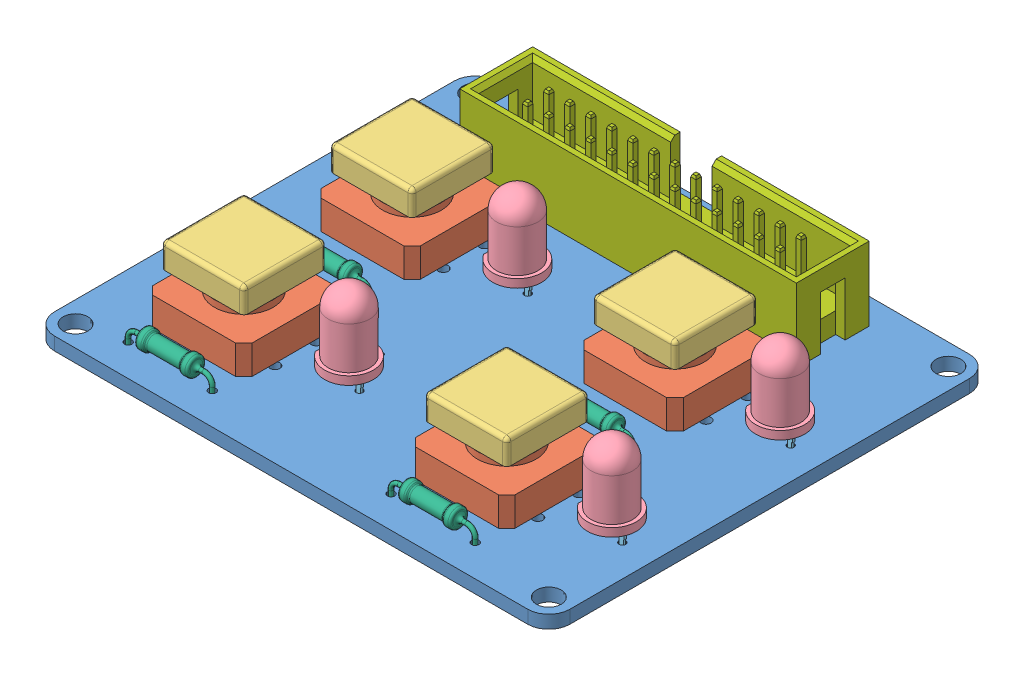
SolidWorks assembly Assembled PCB, configuration Default. Lengths in mm.
Overall size (62.23 14.18 53.34).
30 component instances, 7 part files, 39 mates.
Components (placement in the parent):
- PCB-1: PCB [Default] at (23.5423 23.7207 53.0141) size (62.23 1.57 53.34)
- Button Assembly-1: Button Assembly [Default] at (104.7843 22.09 18.5104) size (12 10.4 12)
  - button-1: button [Default] at (-99.657 3.2054 48.4737) size (12 8.9 12)
  - Cap-2: Cap [Default] at (-99.657 12.0054 48.4737) size (10 4.5 10)
- Button Assembly-2: Button Assembly [Default] at (104.7843 22.09 -1.8054) size (12 10.4 12)
  - button-1: button [Default] at (-99.657 3.2054 48.4737) size (12 8.9 12)
  - Cap-2: Cap [Default] at (-99.657 12.0054 48.4737) size (10 4.5 10)
- Button Assembly-3: Button Assembly [Default] at (136.5343 22.09 18.5104) size (12 10.4 12)
  - button-1: button [Default] at (-99.657 3.2054 48.4737) size (12 8.9 12)
  - Cap-2: Cap [Default] at (-99.657 12.0054 48.4737) size (10 4.5 10)
- Button Assembly-4: Button Assembly [Default] at (136.5343 22.09 -1.8054) size (12 10.4 12)
  - button-1: button [Default] at (-99.657 3.2054 48.4737) size (12 8.9 12)
  - Cap-2: Cap [Default] at (-99.657 12.0054 48.4737) size (10 4.5 10)
- LED short-1: LED short [Default] at (17.8273 29.3722 66.9841) x (-1 0 0) z (0 0 -1) size (5.45 13.1 5.9)
  - LED Head-1: LED Head [Default] at origin size (5.45 8.6 5.9)
  - LED Leads-1: LED Leads [Default] at (0 -5.1452 0) size (4.04 8 0.3)
- LED short-3: LED short [Default] at (17.8273 29.3722 46.6641) x (-1 0 0) z (0 0 -1) size (5.45 13.1 5.9)
  - LED Head-1: LED Head [Default] at origin size (5.45 8.6 5.9)
  - LED Leads-1: LED Leads [Default] at (0 -5.1452 0) size (4.04 8 0.3)
- LED short-4: LED short [Default] at (49.5773 29.3722 46.6641) x (-1 0 0) z (0 0 -1) size (5.45 13.1 5.9)
  - LED Head-1: LED Head [Default] at origin size (5.45 8.6 5.9)
  - LED Leads-1: LED Leads [Default] at (0 -5.1452 0) size (4.04 8 0.3)
- LED short-5: LED short [Default] at (49.5773 29.3722 66.9841) x (-1 0 0) z (0 0 -1) size (5.45 13.1 5.9)
  - LED Head-1: LED Head [Default] at origin size (5.45 8.6 5.9)
  - LED Leads-1: LED Leads [Default] at (0 -5.1452 0) size (4.04 8 0.3)
- Resistor .4-1: Resistor .4 [Default] at (5.1273 26.7955 56.8241) size (10.67 6.22 2.29)
- Resistor .4-2: Resistor .4 [Default] at (5.1273 26.7955 75.8741) size (10.67 6.22 2.29)
- Resistor .4-3: Resistor .4 [Default] at (36.8773 26.7955 56.8241) x (-1 0 0) z (0 0 -1) size (10.67 6.22 2.29)
- Resistor .4-4: Resistor .4 [Default] at (36.8773 26.7955 75.8741) x (-1 0 0) z (0 0 -1) size (10.67 6.22 2.29)
- header-1: header [Default] at (22.9073 25.3955 33.9641) x (-1 0 0) z (0 0 -1) size (40.64 11.9 8.8)
Mates (geometry in assembly coordinates):
- Concentric1: concentric aligned: cylinder of PCB-1 through (5.1273 23.7207 71.4841) axis (0 1 0) radius 0.9017; cylinder of Button Assembly-1/button-1 through (5.1273 23.6955 71.4841) axis (0 1 0) radius 0.9
- Parallel1: parallel aligned: cylinder of PCB-1 through (5.1273 23.7207 62.4883) axis (0 1 0) radius 0.9017; cylinder of Button Assembly-1/button-1 through (5.1273 23.6955 62.4841) axis (0 1 0) radius 0.9
- Coincident1: coincident anti-aligned: plane of PCB-1 through (52.1173 25.2955 28.8841) normal (0 1 0); plane of Button Assembly-1/button-1 through (5.1273 25.2955 66.9841) normal (0 -1 0)
- Concentric3: concentric aligned: cylinder of PCB-1 through (5.1273 23.7207 42.1683) axis (0 1 0) radius 0.9017; cylinder of Button Assembly-2/button-1 through (5.1273 23.6955 42.1683) axis (0 1 0) radius 0.9
- Parallel2: parallel aligned: cylinder of PCB-1 through (5.1273 23.7207 51.1641) axis (0 1 0) radius 0.9017; cylinder of Button Assembly-2/button-1 through (5.1273 23.6955 51.1683) axis (0 1 0) radius 0.9
- Coincident2: coincident anti-aligned: plane of PCB-1 through (52.1173 25.2955 28.8841) normal (0 1 0); plane of Button Assembly-2/button-1 through (5.1273 25.2955 46.6683) normal (0 -1 0)
- Concentric5: concentric aligned: cylinder of PCB-1 through (36.8773 23.7207 71.4841) axis (0 1 0) radius 0.9017; cylinder of Button Assembly-3/button-1 through (36.8773 23.6955 71.4841) axis (0 1 0) radius 0.9
- Parallel3: parallel aligned: cylinder of PCB-1 through (36.8773 23.7207 62.4883) axis (0 1 0) radius 0.9017; cylinder of Button Assembly-3/button-1 through (36.8773 23.6955 62.4841) axis (0 1 0) radius 0.9
- Coincident3: coincident anti-aligned: plane of PCB-1 through (52.1173 25.2955 28.8841) normal (0 1 0); plane of Button Assembly-3/button-1 through (36.8773 25.2955 66.9841) normal (0 -1 0)
- Concentric7: concentric aligned: cylinder of PCB-1 through (36.8773 23.7207 42.1683) axis (0 1 0) radius 0.9017; cylinder of Button Assembly-4/button-1 through (36.8773 23.6955 42.1683) axis (0 1 0) radius 0.9
- Parallel4: parallel aligned: cylinder of PCB-1 through (36.8773 23.7207 51.1641) axis (0 1 0) radius 0.9017; cylinder of Button Assembly-4/button-1 through (36.8773 23.6955 51.1683) axis (0 1 0) radius 0.9
- Coincident4: coincident anti-aligned: plane of PCB-1 through (52.1173 25.2955 28.8841) normal (0 1 0); plane of Button Assembly-4/button-1 through (36.8773 25.2955 46.6683) normal (0 -1 0)
- Parallel5: parallel anti-aligned: line of PCB-1 through (-7.5727 25.2955 28.8841) axis (0 0 1); line of LED short-1/LED Head-1 through (15.3273 25.7955 68.5501) axis (0 0 -1)
- Distance2: distance = 2 mm anti-aligned: plane of LED short-1/LED Head-1 through (17.8273 27.2955 66.9841) normal (0 -1 0); plane of PCB-1 through (52.1173 25.2955 28.8841) normal (0 1 0)
- Concentric8: concentric: point of LED short-1/LED Leads-1; cylinder of PCB-1 through (16.5573 23.7207 66.9841) axis (0 1 0) radius 0.4064
- Parallel7: parallel anti-aligned: line of PCB-1 through (-7.5727 25.2955 28.8841) axis (0 0 1); line of LED short-3/LED Head-1 through (15.3273 25.7955 48.2301) axis (0 0 -1)
- Distance4: distance = 2 mm anti-aligned: plane of LED short-3/LED Head-1 through (17.8273 27.2955 46.6641) normal (0 -1 0); plane of PCB-1 through (52.1173 25.2955 28.8841) normal (0 1 0)
- Concentric9: concentric: cylinder of PCB-1 through (16.5573 23.7207 46.6641) axis (0 1 0) radius 0.4064; point of LED short-3/LED Leads-1
- Parallel8: parallel anti-aligned: line of PCB-1 through (-7.5727 25.2955 28.8841) axis (0 0 1); line of LED short-4/LED Head-1 through (47.0773 25.7955 48.2301) axis (0 0 -1)
- Distance5: distance = 2 mm anti-aligned: plane of LED short-4/LED Head-1 through (49.5773 27.2955 46.6641) normal (0 -1 0); plane of PCB-1 through (52.1173 25.2955 28.8841) normal (0 1 0)
- Concentric10: concentric: cylinder of PCB-1 through (48.3073 23.7207 46.6641) axis (0 1 0) radius 0.4064; point of LED short-4/LED Leads-1
- Parallel9: parallel anti-aligned: line of PCB-1 through (-7.5727 25.2955 28.8841) axis (0 0 1); line of LED short-5/LED Head-1 through (47.0773 25.7955 68.5501) axis (0 0 -1)
- Distance6: distance = 2 mm anti-aligned: plane of LED short-5/LED Head-1 through (49.5773 27.2955 66.9841) normal (0 -1 0); plane of PCB-1 through (52.1173 25.2955 28.8841) normal (0 1 0)
- Concentric11: concentric: cylinder of PCB-1 through (48.3073 23.7207 66.9841) axis (0 1 0) radius 0.4064; point of LED short-5/LED Leads-1
- Concentric12: concentric anti-aligned: cylinder of PCB-1 through (0.0473 23.7207 56.8241) axis (0 1 0) radius 0.45; cylinder of Resistor .4-1 through (0.0473 25.7955 56.8241) axis (0 -1 0) radius 0.254
- Concentric13: concentric anti-aligned: cylinder of PCB-1 through (10.2073 23.7207 56.8241) axis (0 1 0) radius 0.45; cylinder of Resistor .4-1 through (10.2073 25.7955 56.8241) axis (0 -1 0) radius 0.254
- Distance7: distance = 1.5 mm: line of Resistor .4-1 through (7.0669 26.7955 56.8241) axis (-1 0 0); plane of PCB-1 through (52.1173 25.2955 28.8841) normal (0 1 0)
- Distance8: distance = 1.5 mm: line of Resistor .4-2 through (7.0669 26.7955 75.8741) axis (-1 0 0); plane of PCB-1 through (52.1173 25.2955 28.8841) normal (0 1 0)
- Concentric14: concentric anti-aligned: cylinder of PCB-1 through (10.2073 23.7207 75.8741) axis (0 1 0) radius 0.45; cylinder of Resistor .4-2 through (10.2073 25.7955 75.8741) axis (0 -1 0) radius 0.254
- Concentric15: concentric anti-aligned: cylinder of PCB-1 through (0.0473 23.7207 75.8741) axis (0 1 0) radius 0.45; cylinder of Resistor .4-2 through (0.0473 25.7955 75.8741) axis (0 -1 0) radius 0.254
- Concentric16: concentric anti-aligned: cylinder of PCB-1 through (41.9573 23.7207 56.8241) axis (0 1 0) radius 0.45; cylinder of Resistor .4-3 through (41.9573 25.7955 56.8241) axis (0 -1 0) radius 0.254
- Distance9: distance = 1.5 mm: line of Resistor .4-3 through (34.9376 26.7955 56.8241) axis (1 0 0); plane of PCB-1 through (52.1173 25.2955 28.8841) normal (0 1 0)
- Concentric17: concentric anti-aligned: cylinder of PCB-1 through (31.7973 23.7207 56.8241) axis (0 1 0) radius 0.45; cylinder of Resistor .4-3 through (31.7973 25.7955 56.8241) axis (0 -1 0) radius 0.254
- Concentric18: concentric anti-aligned: cylinder of PCB-1 through (41.9573 23.7207 75.8741) axis (0 1 0) radius 0.45; cylinder of Resistor .4-4 through (41.9573 25.7955 75.8741) axis (0 -1 0) radius 0.254
- Distance10: distance = 1.5 mm: line of Resistor .4-4 through (34.9376 26.7955 75.8741) axis (1 0 0); plane of PCB-1 through (52.1173 25.2955 28.8841) normal (0 1 0)
- Concentric19: concentric anti-aligned: cylinder of PCB-1 through (31.7973 23.7207 75.8741) axis (0 1 0) radius 0.45; cylinder of Resistor .4-4 through (31.7973 25.7955 75.8741) axis (0 -1 0) radius 0.254
- Distance11: distance = 0.1 mm anti-aligned: plane of header-1 through (22.9073 25.3955 33.9641) normal (0 -1 0); plane of PCB-1 through (52.1173 25.2955 28.8841) normal (0 1 0)
- Parallel10: parallel anti-aligned: plane of PCB-1 through (-5.0327 25.2955 26.3441) normal (0 0 -1); plane of header-1 through (43.2273 27.8955 38.3641) normal (0 0 1)
- Concentric20: concentric: point of header-1; cylinder of PCB-1 through (38.1473 23.7207 32.6941) axis (0 1 0) radius 0.508
